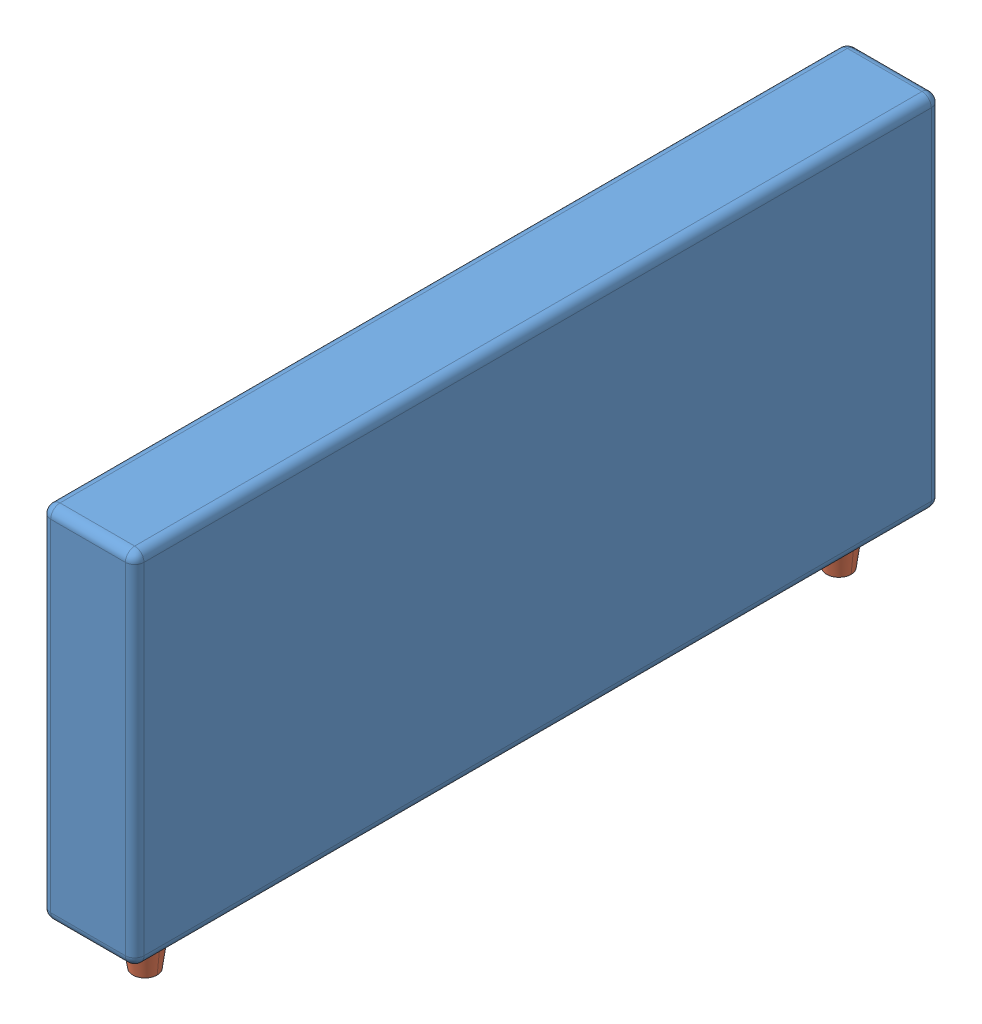
SolidWorks assembly Seitenwand-Kurz, configuration Standard. Lengths in mm.
Overall size (104.2 437.81 867.54).
3 component instances, 2 part files, 9 mates.
Components (placement in the parent):
- Seitenwand-Kurz-1: Seitenwand-Kurz [Standard] at (-1150 3.006 -1510) x (-1 0 0) z (0 1 0) size (104.2 867.54 385.27)
- Standfuss-1: Standfuss [Standard] at (-60.9826 4.7078 -1512.6869) x (-1 0 0) z (0 0.999999 0.001172) size (43.37 42.87 53.74)
- Standfuss-2: Standfuss [Standard] at (-60.9826 4.7078 -2256.0144) x (-1 0 0) z (0 0.999999 0.001172) size (43.37 42.87 53.74)
Mates (geometry in assembly coordinates):
- Deckungsgleich1: coincident anti-aligned: plane of Seitenwand-Kurz-1 through (151.2556 -385.1922 -863.3474) normal (0 -1 0); plane of Standfuss-1 through (227.4888 -385.1922 -92.1385) normal (0 1 0)
- Deckungsgleich2: coincident anti-aligned: plane of Seitenwand-Kurz-1 through (151.2556 -385.1922 -863.3474) normal (0 -1 0); plane of Standfuss-2 through (227.4888 -385.1922 -835.466) normal (0 1 0)
- Abstand1: distance = 40 mm: line of Standfuss-2 through (-50 -436.9945 -804.3705) axis (0 0.999801 0.019937); line of Seitenwand-Kurz-1 through (-10 -385.1922 -10) axis (0 0 -1)
- Abstand2: distance = 50 mm: line of Standfuss-2 through (-50 -436.9945 -804.3705) axis (0 0.999801 0.019937); line of Seitenwand-Kurz-1 through (-90 -385.1922 -853.3474) axis (1 0 0)
- Abstand3: distance = 50 mm: line of Standfuss-1 through (-50 -436.9945 -61.0429) axis (0 0.999801 0.019937); line of Seitenwand-Kurz-1 through (-10 -385.1922 -10) axis (-1 0 0)
- Abstand4: distance = 40 mm: line of Standfuss-1 through (-50 -436.9945 -61.0429) axis (0 0.999801 0.019937); line of Seitenwand-Kurz-1 through (-10 -385.1922 -10) axis (0 0 -1)
- Deckungsgleich7: coincident aligned: plane of Seitenwand-Kurz-1 through (-100 0 -863.3474) normal (0 1 0); plane of assembly
- Deckungsgleich8: coincident aligned: plane of Seitenwand-Kurz-1 through (0 0 0) normal (0 0 1); plane of assembly
- Deckungsgleich9: coincident aligned: plane of Seitenwand-Kurz-1 through (0 0 -863.3474) normal (1 0 0); plane of assembly
